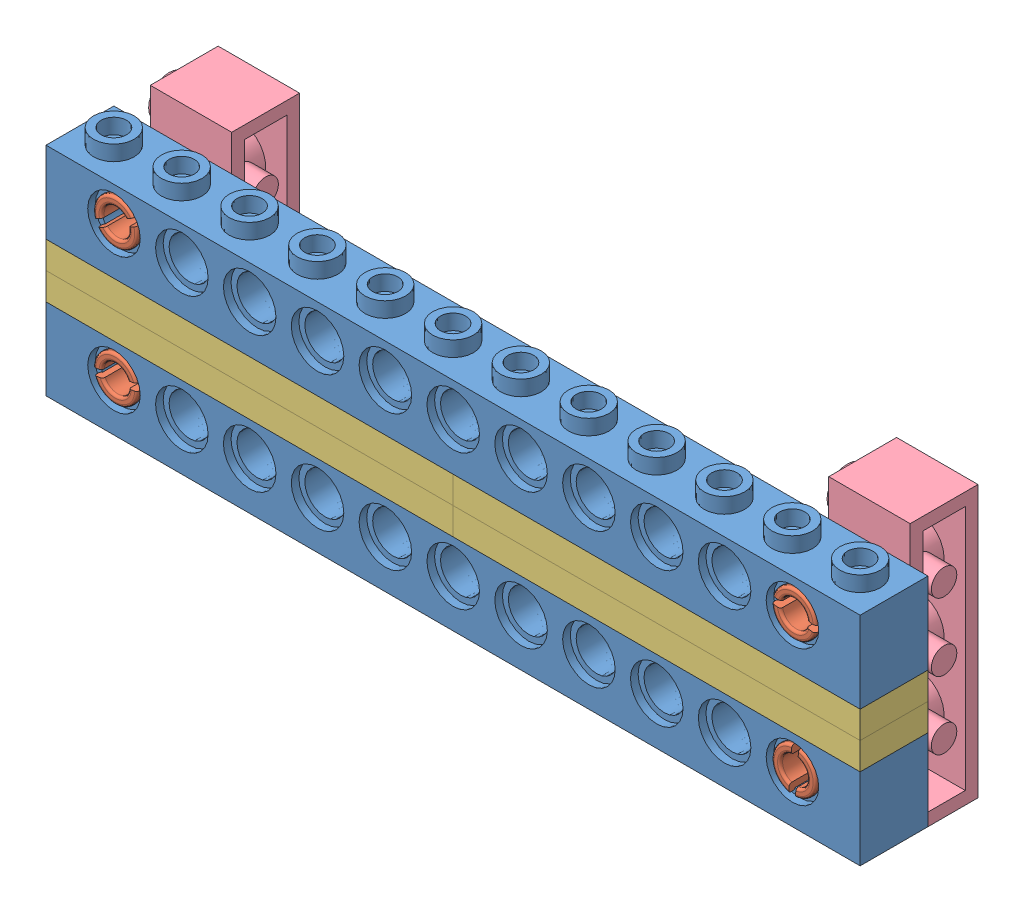
SolidWorks assembly Assembly, configuration Default. Lengths in mm.
Overall size (96 32.03 16.28).
12 component instances, 4 part files, 23 mates.
Components (placement in the parent):
- 1x12 beam-1: 1x12 beam [Default] at (-15.7002 41.5897 73.4612) size (96 11.4 8)
- 9.1.3-1: 9.1.3 [Other Side] at (72.3173 47.1897 73.3212) x (-0.076228 -0.99709 0) z (-0.99709 0.076228 0) size (6 16.04 5.97)
- 1x6 plate-1: 1x6 plate [Default] at (-15.7002 51.1897 81.4612) x (1 0 0) z (0 1 0) size (48 8 5)
- 1x6 plate-2: 1x6 plate [Default] at (32.2998 51.1897 81.4612) x (1 0 0) z (0 1 0) size (48 8 5)
- 1x12 beam-2: 1x12 beam [Default] at (-15.7002 57.5897 73.4612) size (96 11.4 8)
- 1x6 plate-3: 1x6 plate [Default] at (32.2998 54.3897 81.4612) x (1 0 0) z (0 1 0) size (48 8 5)
- 1x6 plate-4: 1x6 plate [Default] at (-15.7002 54.3897 81.4612) x (1 0 0) z (0 1 0) size (48 8 5)
- 1x4 beam-1: 1x4 beam [Default] at (77.9173 71.2072 73.1812) x (0 -1 0) z (0 0 -1) size (32 11.4 8)
- 9.1.3-6: 9.1.3 [Other Side] at (72.3173 63.1897 73.3212) x (-0.993162 0.116746 0) z (0.116746 0.993162 0) size (6 16.04 5.97)
- 9.1.3-7: 9.1.3 [Other Side] at (-7.6827 63.1897 73.3212) x (0.890587 0.454812 0) z (0.454812 -0.890587 0) size (6 16.04 5.97)
- 9.1.3-8: 9.1.3 [Other Side] at (-7.6827 47.1897 73.3212) x (-0.987343 -0.158599 0) z (-0.158599 0.987343 0) size (6 16.04 5.97)
- 1x4 beam-2: 1x4 beam [Default] at (-2.0827 39.1722 65.1812) x (0 1 0) z (0 0 1) size (32 11.4 8)
Mates (geometry in assembly coordinates):
- Coincident6: coincident: point of 1x12 beam-1; point of 1x6 plate-1
- Coincident7: coincident: point of 1x12 beam-1; point of 1x6 plate-1
- Coincident8: coincident: moEndPointRef_w of 1x12 beam-1; point of 1x6 plate-1
- Coincident9: coincident: point of 1x6 plate-1; point of 1x6 plate-2
- Coincident10: coincident: line of 1x12 beam-1 through (80.2998 51.1897 73.4612) axis (-1 0 0); point of 1x6 plate-2
- Coincident12: coincident: point of 1x12 beam-1; point of 1x6 plate-2
- Coincident13: coincident: point of 1x6 plate-1; point of 1x6 plate-4
- Coincident16: coincident: point of 1x6 plate-1; point of 1x6 plate-4
- Coincident17: coincident: plane of 1x6 plate-1 through (-15.7002 54.3897 81.4612) normal (0 1 0); point of 1x6 plate-4
- Coincident18: coincident: point of 1x6 plate-3; point of 1x6 plate-4
- Coincident19: coincident: point of 1x6 plate-3; point of 1x6 plate-4
- Coincident20: coincident: point of 1x6 plate-2; point of 1x6 plate-3
- Coincident21: coincident: point of 1x12 beam-2; point of 1x6 plate-3
- Coincident22: coincident: point of 1x12 beam-2; point of 1x6 plate-3
- Coincident23: coincident: point of 1x12 beam-2; point of 1x6 plate-4
- Coincident30: coincident aligned: circle of 1x12 beam-1; circle of 9.1.3-1
- Coincident32: coincident aligned: circle of 1x12 beam-2; circle of 9.1.3-6
- Coincident35: coincident anti-aligned: circle of 1x4 beam-1; circle of 9.1.3-6
- Coincident37: coincident anti-aligned: circle of 9.1.3-1; circle of 1x4 beam-1
- Coincident39: coincident aligned: circle of 1x12 beam-2; circle of 9.1.3-7
- Coincident40: coincident aligned: circle of 1x12 beam-1; circle of 9.1.3-8
- Coincident41: coincident aligned: circle of 9.1.3-7; circle of 1x4 beam-2
- Coincident42: coincident aligned: circle of 9.1.3-8; circle of 1x4 beam-2
